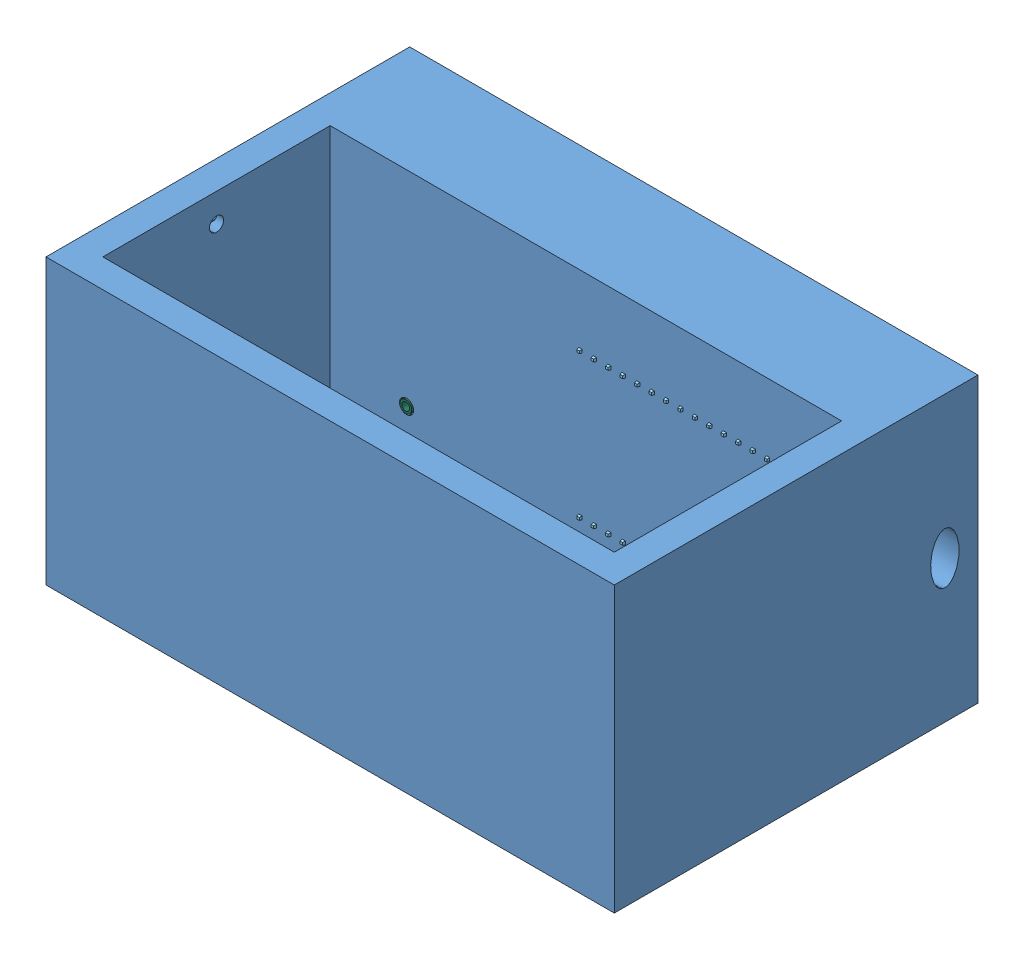
SolidWorks assembly Differential Pressure Device Assembly, configuration Default. Lengths in mm.
Overall size (100 50 64).
60 component instances, 15 part files, 0 mates.
Components (placement in the parent):
- Pythagoras Container-1: Pythagoras Container [Default] at (21.0479 31.6531 89.3137) size (100 50 64)
- esp32_dev_kit_v1_asm.stp-1: esp32_dev_kit_v1_asm.stp [Default] at (65.3978 56.7487 59.1916) x (0 -1 0) z (0 0 -1) size (28.15 51.52 15.01)
  - BUTTON_R_ASM.stp-1: BUTTON_R_ASM.stp [Default] at (-14.325 24.4 0) x (1 0 0) z (0 -1 0) size (3 1.98 5.54)
    - BUTTONFLASH-13_2.stp-1: BUTTONFLASH-13_2.stp [Default] at origin size (1.75 0.75 1.75)
    - BUTTONFLASH-14_2.stp-1: BUTTONFLASH-14_2.stp [Default] at origin size (3 1.7 5.54)
  - BUTTON_R_ASM.stp-2: BUTTON_R_ASM.stp [Default] at (1.825 24.4 0) x (1 0 0) z (0 -1 0) size (3 1.98 5.54)
    - BUTTONFLASH-13_2.stp-1: BUTTONFLASH-13_2.stp [Default] at origin size (1.75 0.75 1.75)
    - BUTTONFLASH-14_2.stp-1: BUTTONFLASH-14_2.stp [Default] at origin size (3 1.7 5.54)
  - PCB.stp-1: PCB.stp [Default] x (0 0 1) z (1 0 0) size (1.6 51.5 28.15)
  - PIN.stp-1: PIN.stp [Default] at (12.7 -8.03 0) x (0 1 0) z (-1 0 0) size (2.54 13.54 2.5)
  - PIN.stp-2: PIN.stp [Default] at (12.7 -5.49 0) x (0 1 0) z (-1 0 0) size (2.54 13.54 2.5)
  - PIN.stp-3: PIN.stp [Default] at (12.7 -2.95 0) x (0 1 0) z (-1 0 0) size (2.54 13.54 2.5)
  - PIN.stp-4: PIN.stp [Default] at (12.7 -0.41 0) x (0 1 0) z (-1 0 0) size (2.54 13.54 2.5)
  - PIN.stp-5: PIN.stp [Default] at (12.7 2.13 0) x (0 1 0) z (-1 0 0) size (2.54 13.54 2.5)
  - PIN.stp-6: PIN.stp [Default] at (12.7 4.67 0) x (0 1 0) z (-1 0 0) size (2.54 13.54 2.5)
  - PIN.stp-7: PIN.stp [Default] at (12.7 7.21 0) x (0 1 0) z (-1 0 0) size (2.54 13.54 2.5)
  - PIN.stp-8: PIN.stp [Default] at (12.7 9.75 0) x (0 1 0) z (-1 0 0) size (2.54 13.54 2.5)
  - PIN.stp-9: PIN.stp [Default] at (12.7 12.29 0) x (0 1 0) z (-1 0 0) size (2.54 13.54 2.5)
  - PIN.stp-10: PIN.stp [Default] at (12.7 14.83 0) x (0 1 0) z (-1 0 0) size (2.54 13.54 2.5)
  - PIN.stp-11: PIN.stp [Default] at (12.7 17.37 0) x (0 1 0) z (-1 0 0) size (2.54 13.54 2.5)
  - PIN.stp-12: PIN.stp [Default] at (12.7 19.91 0) x (0 1 0) z (-1 0 0) size (2.54 13.54 2.5)
  - PIN.stp-13: PIN.stp [Default] at (12.7 22.45 0) x (0 1 0) z (-1 0 0) size (2.54 13.54 2.5)
  - PIN.stp-14: PIN.stp [Default] at (12.7 24.99 0) x (0 1 0) z (-1 0 0) size (2.54 13.54 2.5)
  - PIN.stp-15: PIN.stp [Default] at (12.7 27.53 0) x (0 1 0) z (-1 0 0) size (2.54 13.54 2.5)
  - PIN.stp-16: PIN.stp [Default] at (-12.7 27.53 0) x (0 -1 0) z (1 0 0) size (2.54 13.54 2.5)
  - PIN.stp-17: PIN.stp [Default] at (-12.7 30.07 0) x (0 -1 0) z (1 0 0) size (2.54 13.54 2.5)
  - PIN.stp-18: PIN.stp [Default] at (-12.7 32.61 0) x (0 -1 0) z (1 0 0) size (2.54 13.54 2.5)
  - PIN.stp-19: PIN.stp [Default] at (-12.7 35.15 0) x (0 -1 0) z (1 0 0) size (2.54 13.54 2.5)
  - PIN.stp-20: PIN.stp [Default] at (-12.7 37.69 0) x (0 -1 0) z (1 0 0) size (2.54 13.54 2.5)
  - PIN.stp-21: PIN.stp [Default] at (-12.7 40.23 0) x (0 -1 0) z (1 0 0) size (2.54 13.54 2.5)
  - PIN.stp-22: PIN.stp [Default] at (-12.7 42.77 0) x (0 -1 0) z (1 0 0) size (2.54 13.54 2.5)
  - PIN.stp-23: PIN.stp [Default] at (-12.7 45.31 0) x (0 -1 0) z (1 0 0) size (2.54 13.54 2.5)
  - PIN.stp-24: PIN.stp [Default] at (-12.7 47.85 0) x (0 -1 0) z (1 0 0) size (2.54 13.54 2.5)
  - PIN.stp-25: PIN.stp [Default] at (-12.7 50.39 0) x (0 -1 0) z (1 0 0) size (2.54 13.54 2.5)
  - PIN.stp-26: PIN.stp [Default] at (-12.7 52.93 0) x (0 -1 0) z (1 0 0) size (2.54 13.54 2.5)
  - PIN.stp-27: PIN.stp [Default] at (-12.7 55.47 0) x (0 -1 0) z (1 0 0) size (2.54 13.54 2.5)
  - PIN.stp-28: PIN.stp [Default] at (-12.7 58.01 0) x (0 -1 0) z (1 0 0) size (2.54 13.54 2.5)
  - PIN.stp-29: PIN.stp [Default] at (-12.7 60.55 0) x (0 -1 0) z (1 0 0) size (2.54 13.54 2.5)
  - PIN.stp-30: PIN.stp [Default] at (-12.7 63.09 0) x (0 -1 0) z (1 0 0) size (2.54 13.54 2.5)
  - WIFI_CARD_2.stp-1: WIFI_CARD_2.stp [Default] at (0 27.175 -0.055) x (1 0 0) z (0 -1 0) size (16.03 2.81 24.02)
  - RECTANGULARCHIP_2.stp-1: RECTANGULARCHIP_2.stp [Default] at (-3.825 8.35 -0.051) x (-1 0 0) z (0 1 0) size (7.45 1.65 6)
  - MICROCHIP_2.stp-1: MICROCHIP_2.stp [Default] at (4.825 26.75 -0.052) x (1 0 0) z (0 -1 0) size (6.2 1 6.2)
  - TANCHIP_2.stp-1: TANCHIP_2.stp [Default] at (-1.725 10.65 -0.052) x (0 -1 0) z (-1 0 0) size (2.9 2 4.98)
  - TRANSISTOR_3-LEG_2.stp-1: TRANSISTOR_3-LEG_2.stp [Default] at (0.025 10.5 -0.052) x (0 1 0) z (1 0 0) size (3 0.79 2.31)
  - RESISTOR1_2.stp-1: RESISTOR1_2.stp [Default] at (-5.125 26 -0.051) x (0 1 0) z (1 0 0) size (2.1 0.4 0.9)
  - RESISTOR1_2.stp-2: RESISTOR1_2.stp [Default] at (-3.375 26 -0.051) x (0 1 0) z (1 0 0) size (2.1 0.4 0.9)
  - RESISTOR1_2.stp-3: RESISTOR1_2.stp [Default] at (-1.625 26 -0.051) x (0 1 0) z (1 0 0) size (2.1 0.4 0.9)
  - RESISTOR1_2.stp-4: RESISTOR1_2.stp [Default] at (0.125 26 -0.051) x (0 1 0) z (1 0 0) size (2.1 0.4 0.9)
  - RESISTOR1_2.stp-5: RESISTOR1_2.stp [Default] at (1.875 26 -0.051) x (0 1 0) z (1 0 0) size (2.1 0.4 0.9)
  - RESISTOR2-32_2.stp-1: RESISTOR2-32_2.stp [Default] at (3.825 31.3 -0.051) x (1 0 0) z (0 -1 0) size (0.9 0.4 2.1)
  - RESISTOR2-32_2.stp-2: RESISTOR2-32_2.stp [Default] at (-6.675 31.3 -0.051) x (1 0 0) z (0 -1 0) size (0.9 0.4 2.1)
  - RESISTOR1_2.stp-6: RESISTOR1_2.stp [Default] at (11.575 23 -0.051) x (1 0 0) z (0 -1 0) size (2.1 0.4 0.9)
  - RESISTOR1_2.stp-7: RESISTOR1_2.stp [Default] at (11.575 24.2 -0.051) x (1 0 0) z (0 -1 0) size (2.1 0.4 0.9)
  - RESISTOR1_2.stp-8: RESISTOR1_2.stp [Default] at (-3.625 23 -0.051) x (1 0 0) z (0 -1 0) size (2.1 0.4 0.9)
  - RESISTOR1_2.stp-9: RESISTOR1_2.stp [Default] at (-3.625 24.2 -0.051) x (1 0 0) z (0 -1 0) size (2.1 0.4 0.9)
  - TRANSISTOR_3-LEG2_2.stp-1: TRANSISTOR_3-LEG2_2.stp [Default] at (-12.335 10.54 -0.052) x (0 1 0) z (1 0 0) size (3 0.79 2.31)
  - RESISTOR1_2.stp-10: RESISTOR1_2.stp [Default] at (7.375 21.9 -0.051) x (0 1 0) z (1 0 0) size (2.1 0.4 0.9)
  - RESISTOR1_2.stp-11: RESISTOR1_2.stp [Default] at (-3.375 21.9 -0.051) x (0 1 0) z (1 0 0) size (2.1 0.4 0.9)
  - USB_SOCKET_2.stp-1: USB_SOCKET_2.stp [Default] at (0 24.41 -0.06) x (1 0 0) z (0 -1 0) size (8.01 2.95 5.7)
- Differential Pressure Sensor-1: Differential Pressure Sensor [bottom] at (-10.1196 42.8557 61.7763) x (-1 0 0) z (0 0 1) size (11.6 7.7 11.68)
